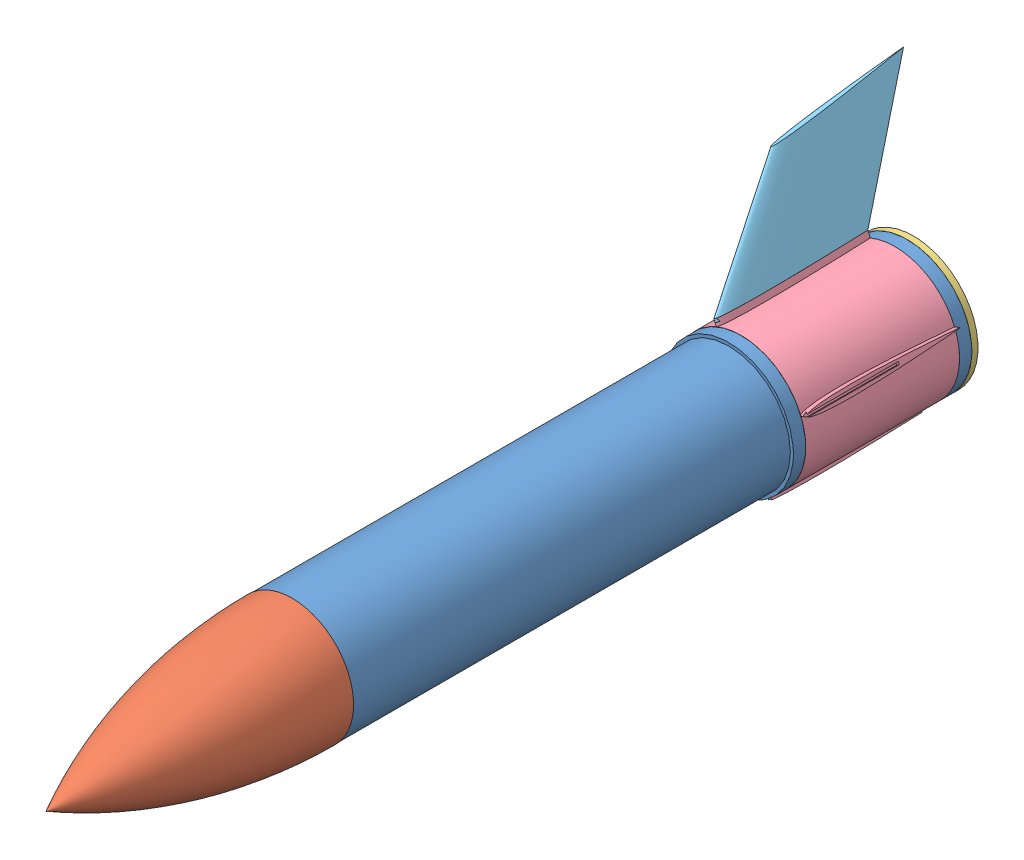
SolidWorks assembly Single_Stage, configuration Default. Lengths in mm.
Overall size (60.11 85 301.69).
5 component instances, 5 part files, 9 mates.
Components (placement in the parent):
- Body_Tube-1: Body_Tube [Default] at (66.6706 102.1961 59.2077) size (42 42 200)
- Nose_Cone-1: Nose_Cone [Default] at (66.6706 102.1961 339.2077) size (40 40 90)
- Motor_Mount-1: Motor_Mount [Default] at (66.6706 102.1961 57.2077) size (42 42 71)
- Fin_Ring-1: Fin_Ring [Default] at (66.6706 102.1961 113.2077) x (-0.923728 -0.383049 0) z (0 0 -1) size (46 46 53.05)
- Fins-1: Fins [Default] at (57.8605 123.4419 113.2077) x (0.923728 0.383049 0) z (0 0 1) size (3.84 36.69 75.69)
Mates (geometry in assembly coordinates):
- Concentric1: concentric anti-aligned: cylinder of Body_Tube-1 through (66.6706 102.1961 259.2077) axis (0 0 -1) radius 18; cylinder of Nose_Cone-1 through (66.6706 102.1961 339.2077) axis (0 0 1) radius 18
- Coincident1: coincident anti-aligned: plane of Body_Tube-1 through (66.6706 102.1961 259.2077) normal (0 0 1); plane of Nose_Cone-1 through (66.6706 122.1961 259.2077) normal (0 0 -1)
- Concentric2: concentric aligned: cylinder of Body_Tube-1 through (66.6706 102.1961 259.2077) axis (0 0 -1) radius 18; cylinder of Motor_Mount-1 through (66.6706 102.1961 127.2077) axis (0 0 -1) radius 13
- Coincident2: coincident anti-aligned: plane of Body_Tube-1 through (66.6706 102.1961 59.2077) normal (0 0 -1); plane of Motor_Mount-1 through (66.6706 102.1961 59.2077) normal (0 0 1)
- Coincident6: coincident anti-aligned: plane of Body_Tube-1 through (66.6706 102.1961 113.2077) normal (0 0 -1); plane of Fin_Ring-1 through (66.6706 102.1961 113.2077) normal (0 0 1)
- Concentric4: concentric anti-aligned: cylinder of Body_Tube-1 through (66.6706 102.1961 259.2077) axis (0 0 -1) radius 20; cylinder of Fin_Ring-1 through (66.6706 102.1961 63.2077) axis (0 0 1) radius 20
- Coincident7: coincident: plane of Fin_Ring-1 through (58.7977 122.748 83.2077) normal (-0.830668 -0.556768 0); plane of Fins-1 through (58.2299 123.5951 130.7748) normal (0.830668 0.556768 0)
- Coincident8: coincident: plane of Fin_Ring-1 through (57.6893 122.2883 83.2077) normal (-0.383049 0.923728 0); plane of Fins-1 through (57.6893 122.2883 130.7748) normal (0.383049 -0.923728 0)
- Coincident9: coincident anti-aligned: plane of Fin_Ring-1 through (66.6706 102.1961 83.2077) normal (0 0 1); plane of Fins-1 through (57.8605 123.4419 83.2077) normal (0 0 -1)
